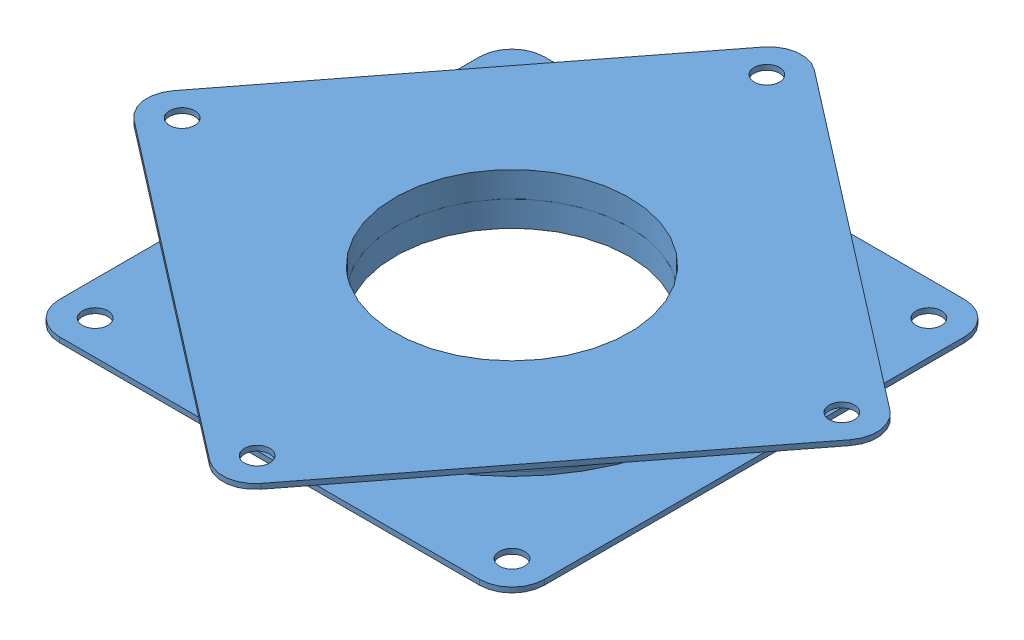
SolidWorks assembly ThrustBearing, configuration Default. Lengths in mm.
Overall size (106.89 8 106.89).
2 component instances, 1 part files, 1 mates.
Components (placement in the parent):
- BearingPart-1: BearingPart [Default] at (-116.9051 10.4623 53.2225) size (76.2 4 76.2)
- BearingPart-2: BearingPart [Default] at (-116.9051 18.4623 53.2225) x (-0.791311 0 -0.611413) z (-0.611413 0 0.791311) size (76.2 4 76.2)
Mates (geometry in assembly coordinates):
- Coincident1: coincident anti-aligned: circle of BearingPart-1; circle of BearingPart-2
